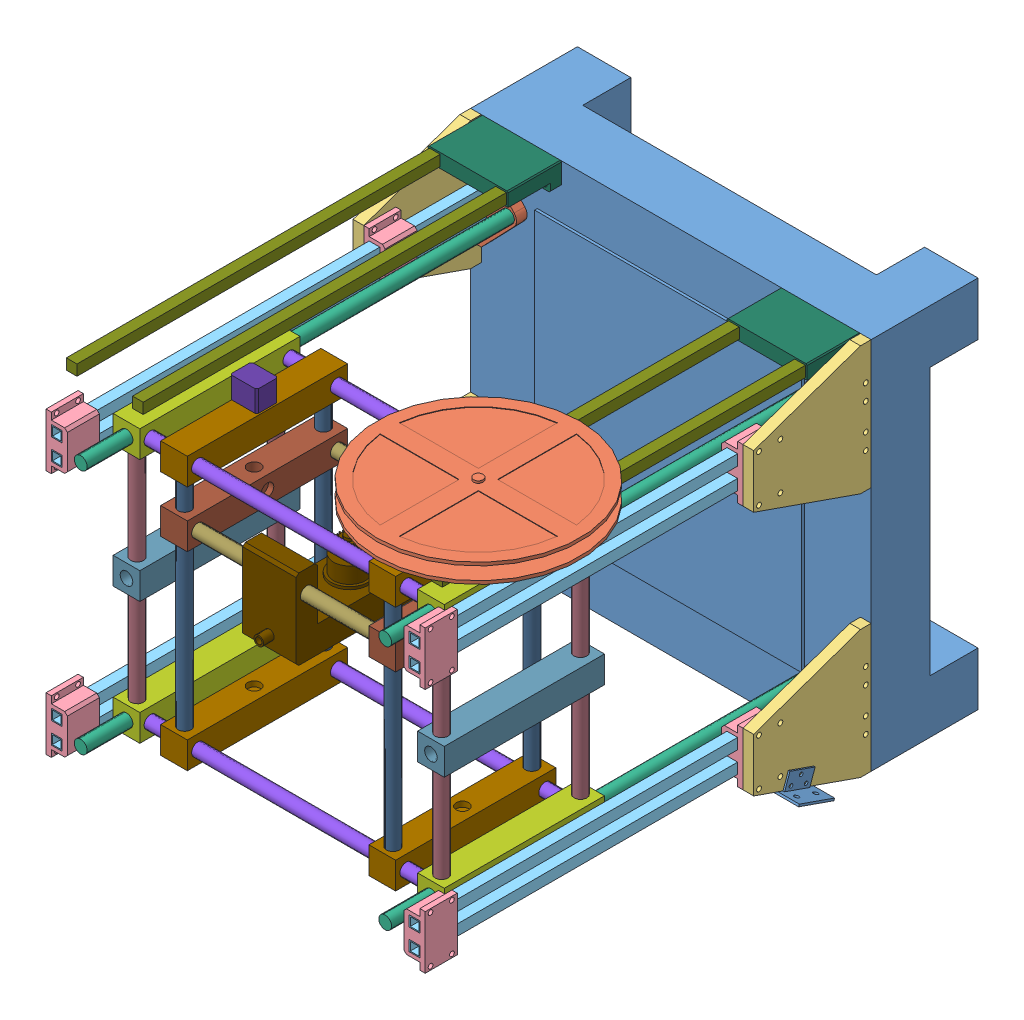
SolidWorks assembly ASSEMBLY, configuration Default. Lengths in mm.
Overall size (422.5 377.5 515.25).
70 component instances, 20 part files, 161 mates.
Components (placement in the parent):
- BASE-1: BASE [Default] at (119.7279 200.2172 245.0572) size (375 352.5 102.5)
- BOTTOM SUPPORT-1: BOTTOM SUPPORT [Default] at (292.2279 315.2172 355.0572) x (0 -1 0) z (0 0 -1) size (75 43 60)
- BOTTOM SUPPORT-2: BOTTOM SUPPORT [Default] at (-52.7721 315.2172 355.0572) x (0 1 0) z (0 0 -1) size (75 43 60)
- BOTTOM SUPPORT-3: BOTTOM SUPPORT [Default] at (-52.7721 85.2172 355.0572) x (0 1 0) z (0 0 -1) size (75 43 60)
- BOTTOM SUPPORT-4: BOTTOM SUPPORT [Default] at (292.2279 85.2172 355.0572) x (0 -1 0) z (0 0 -1) size (75 43 60)
- SIDE SUPPORT-1: SIDE SUPPORT [Default] at (297.2279 315.2172 350.0572) x (0 1 0) z (1 0 0) size (120 110 10)
- SIDE SUPPORT-2: SIDE SUPPORT [Default] at (297.2279 85.2172 350.0572) x (0 1 0) z (1 0 0) size (120 110 10)
- SIDE SUPPORT-3: SIDE SUPPORT [Default] at (-67.7721 85.2172 350.0572) x (0 1 0) z (1 0 0) size (120 110 10)
- SIDE SUPPORT-4: SIDE SUPPORT [Default] at (-67.7721 315.2172 350.0572) x (0 1 0) z (1 0 0) size (120 110 10)
- SIDE KNOB-1: SIDE KNOB [Default] at (287.2279 85.2172 425.0572) x (0 1 0) z (0 0 1) size (50 20 30)
- SIDE KNOB-2: SIDE KNOB [Default] at (287.2279 315.2172 455.0572) x (0 -1 0) z (0 0 -1) size (50 20 30)
- SIDE KNOB-3: SIDE KNOB [Default] at (-47.7721 315.2172 455.0572) x (0 1 0) z (0 0 -1) size (50 20 30)
- SIDE KNOB-4: SIDE KNOB [Default] at (-47.7721 85.2172 455.0572) x (0 1 0) z (0 0 -1) size (50 20 30)
- SQUARE ROD-1: SQUARE ROD [Default] at (-47.7721 75.2172 352.5572) size (10 10 400)
- SQUARE ROD-2: SQUARE ROD [Default] at (-47.7721 95.2172 352.5572) size (10 10 400)
- SQUARE ROD-3: SQUARE ROD [Default] at (-47.7721 305.2172 352.5572) size (10 10 400)
- SQUARE ROD-4: SQUARE ROD [Default] at (-47.7721 325.2172 352.5572) size (10 10 400)
- SQUARE ROD-5: SQUARE ROD [Default] at (287.2279 75.2172 352.5572) size (10 10 400)
- SQUARE ROD-6: SQUARE ROD [Default] at (287.2279 95.2172 352.5572) size (10 10 400)
- SQUARE ROD-7: SQUARE ROD [Default] at (287.2279 305.2172 352.5572) size (10 10 400)
- SQUARE ROD-8: SQUARE ROD [Default] at (287.2279 325.2172 352.5572) size (10 10 400)
- VERTICAL GUIDE-1: VERTICAL GUIDE [Default] at (-22.7721 85.2172 345.0572) x (0.761776 0.647841 0) z (0 0 1) size (12 12 410)
- VERTICAL GUIDE-2: VERTICAL GUIDE [Default] at (-22.7721 315.2172 345.0572) x (0.761776 0.647841 0) z (0 0 1) size (12 12 410)
- VERTICAL GUIDE-3: VERTICAL GUIDE [Default] at (262.2279 315.2172 345.0572) x (0.980683 -0.195602 0) z (0 0 1) size (12 12 410)
- VERTICAL GUIDE-4: VERTICAL GUIDE [Default] at (262.2279 85.2172 345.0572) x (0.443142 0.896451 0) z (0 0 1) size (12 12 410)
- new idea side knob-1: new idea side knob [Default] at (-22.7721 85.2172 637.218) x (0 -1 0) z (0 0 1) size (25 25 150)
- new idea side knob-2: new idea side knob [Default] at (-22.7721 315.2172 637.218) x (-1 0 0) z (0 0 1) size (25 25 150)
- new idea side knob-3: new idea side knob [Default] at (262.2279 315.2172 637.218) x (0 1 0) z (0 0 1) size (25 25 150)
- new idea side knob-4: new idea side knob [Default] at (262.2279 85.2172 637.218) size (25 25 150)
- FRONT GUIDE-1: FRONT GUIDE [Default] at (-15.2721 85.2172 702.218) x (0 -0.395369 -0.918522) z (1 0 0) size (12 12 270)
- FRONT GUIDE-2: FRONT GUIDE [Default] at (-15.2721 85.2172 572.218) x (0 -0.335752 -0.94195) z (1 0 0) size (12 12 270)
- FRONT GUIDE-3: FRONT GUIDE [Default] at (-15.2721 315.2172 702.218) x (0 0.992345 0.123494) z (1 0 0) size (12 12 270)
- FRONT GUIDE-4: FRONT GUIDE [Default] at (-15.2721 315.2172 572.218) x (0 0.188743 0.982026) z (1 0 0) size (12 12 270)
- front and back knob new idea-1: front and back knob new idea [Default] at (21.6908 85.2172 637.218) size (25 25 150)
- front and back knob new idea-2: front and back knob new idea [Default] at (216.6908 85.2172 637.218) size (25 25 150)
- front and back knob new idea-3: front and back knob new idea [Default] at (21.6908 315.2172 637.218) x (1 0 0) z (0 0 -1) size (25 25 150)
- front and back knob new idea-4: front and back knob new idea [Default] at (216.6908 315.2172 637.218) x (1 0 0) z (0 0 -1) size (25 25 150)
- HORIZONTAL ROD-1: HORIZONTAL ROD [Default] at (216.6908 92.7172 702.218) x (0.99237 0 -0.123294) z (0 1 0) size (12 12 215)
- HORIZONTAL ROD-2: HORIZONTAL ROD [Default] at (216.6908 92.7172 572.218) x (0.99237 0 -0.123294) z (0 1 0) size (12 12 215)
- HORIZONTAL ROD-3: HORIZONTAL ROD [Default] at (21.6908 92.7172 572.218) x (0.993205 0 0.116374) z (0 1 0) size (12 12 215)
- HORIZONTAL ROD-5: HORIZONTAL ROD [Default] at (21.6908 92.7172 702.218) x (0.993205 0 0.116374) z (0 1 0) size (12 12 215)
- new idea knob-1: new idea knob [Default] at (216.6908 262.7791 637.218) x (0 1 0) z (0 0 1) size (25 25 150)
- new idea knob-2: new idea knob [Default] at (21.6908 262.7791 637.218) x (0 -1 0) z (0 0 1) size (25 25 150)
- CENTER GUIDE-1: CENTER GUIDE [Default] at (209.1908 262.7791 702.218) x (0 0 1) z (-1 0 0) size (12 12 180)
- CENTER GUIDE-2: CENTER GUIDE [Default] at (209.1908 262.7791 572.218) x (0 0 1) z (-1 0 0) size (12 12 180)
- SIDE KNOB-5: SIDE KNOB [Default] at (-47.7721 85.2172 752.5572) x (0 1 0) z (0 0 -1) size (50 20 30)
- SIDE KNOB-6: SIDE KNOB [Default] at (-47.7721 315.2172 752.5572) x (0 1 0) z (0 0 -1) size (50 20 30)
- SIDE KNOB-7: SIDE KNOB [Default] at (287.2279 85.2172 752.5572) x (0 -1 0) z (0 0 -1) size (50 20 30)
- SIDE KNOB-8: SIDE KNOB [Default] at (287.2279 315.2172 752.5572) x (0 -1 0) z (0 0 -1) size (50 20 30)
- SIDE SIDE ROD-1: SIDE SIDE ROD [Default] at (-22.7721 207.7172 702.218) x (1 0 0) z (0 1 0) size (12 12 100)
- new idea center knob-2: new idea center knob [Default] at (-22.7721 200.2172 637.218) size (25 25 150)
- SIDE SIDE ROD-2: SIDE SIDE ROD [Default] at (-22.7721 192.7172 702.218) x (-0.837169 0 -0.546944) z (0 -1 0) size (12 12 100)
- SIDE SIDE ROD-3: SIDE SIDE ROD [Default] at (-22.7721 192.7172 572.218) x (-0.837169 0 -0.546944) z (0 -1 0) size (12 12 100)
- SIDE SIDE ROD-4: SIDE SIDE ROD [Default] at (-22.7721 307.7172 572.218) x (-0.837169 0 -0.546944) z (0 -1 0) size (12 12 100)
- SIDE SIDE ROD-5: SIDE SIDE ROD [Default] at (262.2279 192.7172 702.218) x (-0.837169 0 -0.546944) z (0 -1 0) size (12 12 100)
- new idea center knob-3: new idea center knob [Default] at (262.2279 200.2172 637.218) size (25 25 150)
- SIDE SIDE ROD-6: SIDE SIDE ROD [Default] at (262.2279 307.7172 702.218) x (-0.837169 0 -0.546944) z (0 -1 0) size (12 12 100)
- SIDE SIDE ROD-7: SIDE SIDE ROD [Default] at (262.2279 192.7172 572.218) x (-0.837169 0 -0.546944) z (0 -1 0) size (12 12 100)
- SIDE SIDE ROD-8: SIDE SIDE ROD [Default] at (262.2279 307.7172 572.218) x (-0.837169 0 -0.546944) z (0 -1 0) size (12 12 100)
- Part1-1: Part1 [Default] at (17.2279 375.2172 345.0572) x (0 -1 0) z (-1 0 0) size (21 50 75)
- Part1-2: Part1 [Default] at (297.2279 375.2172 345.0572) x (0 -1 0) z (-1 0 0) size (21 50 75)
- BACK RAIL-1: BACK RAIL [Default] at (290.7279 368.7172 385.0572) size (10 10 350)
- BACK RAIL-2: BACK RAIL [Default] at (228.7279 368.7172 385.0572) size (10 10 350)
- BACK RAIL-3: BACK RAIL [Default] at (-51.2721 368.7172 735.0572) x (0 -1 0) z (0 0 -1) size (10 10 350)
- BACK RAIL-5: BACK RAIL [Default] at (10.7279 368.7172 385.0572) size (10 10 350)
- MOTOR-2: MOTOR [Default] at (21.6908 349.2172 637.218) x (1 0 0) z (0 -1 0) size (25 20 21.5)
- MOTOR-3: MOTOR [Default] at (216.6908 349.2172 637.218) x (1 0 0) z (0 -1 0) size (25 20 21.5)
- new idea for nozzle-1: new idea for nozzle [Default] at (111.0525 245.2791 637.218) x (0 1 0) z (1 0 0) size (75 173.25 50)
- SCREEN SUPPORT-2: SCREEN SUPPORT [Default] at (302.2279 44.5865 416.452) x (-1 0 0) z (0 0.943858 -0.33035) size (50 35 17)
- TOP SUPPORT-1: TOP SUPPORT [Default] at (259.7279 364.7172 640.3028) size (190 46 190)
Mates (geometry in assembly coordinates):
- Coincident5: coincident anti-aligned: plane of BASE-1 through (297.2279 200.2172 295.0572) normal (-1 0 0); plane of BOTTOM SUPPORT-1 through (297.2279 352.7172 345.0572) normal (1 0 0)
- Coincident6: coincident anti-aligned: plane of BASE-1 through (119.7279 200.2172 295.0572) normal (0 0 1); plane of BOTTOM SUPPORT-1 through (292.2279 315.2172 295.0572) normal (0 0 -1)
- Coincident7: coincident anti-aligned: plane of BASE-1 through (119.7279 277.7172 295.0572) normal (0 1 0); plane of BOTTOM SUPPORT-1 through (297.2279 277.7172 345.0572) normal (0 -1 0)
- Coincident13: coincident anti-aligned: plane of BASE-1 through (-47.7721 200.2172 295.0572) normal (-1 0 0); plane of BOTTOM SUPPORT-2 through (-47.7721 277.7172 295.0572) normal (1 0 0)
- Coincident14: coincident anti-aligned: plane of BASE-1 through (119.7279 352.7172 295.0572) normal (0 -1 0); plane of BOTTOM SUPPORT-2 through (-57.7721 352.7172 345.0572) normal (0 1 0)
- Coincident15: coincident anti-aligned: plane of BASE-1 through (119.7279 200.2172 295.0572) normal (0 0 1); plane of BOTTOM SUPPORT-2 through (-52.7721 315.2172 295.0572) normal (0 0 -1)
- Coincident16: coincident anti-aligned: plane of BASE-1 through (-47.7721 200.2172 295.0572) normal (-1 0 0); plane of BOTTOM SUPPORT-3 through (-47.7721 47.7172 295.0572) normal (1 0 0)
- Coincident17: coincident anti-aligned: plane of BASE-1 through (119.7279 122.7172 295.0572) normal (0 -1 0); plane of BOTTOM SUPPORT-3 through (-57.7721 122.7172 345.0572) normal (0 1 0)
- Coincident18: coincident anti-aligned: plane of BASE-1 through (119.7279 200.2172 295.0572) normal (0 0 1); plane of BOTTOM SUPPORT-3 through (-52.7721 85.2172 295.0572) normal (0 0 -1)
- Coincident19: coincident anti-aligned: plane of BASE-1 through (287.2279 200.2172 295.0572) normal (1 0 0); plane of BOTTOM SUPPORT-4 through (287.2279 122.7172 295.0572) normal (-1 0 0)
- Coincident20: coincident anti-aligned: plane of BASE-1 through (119.7279 122.7172 295.0572) normal (0 -1 0); plane of BOTTOM SUPPORT-4 through (297.2279 122.7172 345.0572) normal (0 1 0)
- Coincident21: coincident anti-aligned: plane of BASE-1 through (119.7279 200.2172 295.0572) normal (0 0 1); plane of BOTTOM SUPPORT-4 through (292.2279 85.2172 295.0572) normal (0 0 -1)
- Concentric1: concentric anti-aligned: cylinder of BOTTOM SUPPORT-1 through (288.2279 287.7172 350.0572) axis (1 0 0) radius 2.25; cylinder of SIDE SUPPORT-1 through (307.2279 287.7172 350.0572) axis (-1 0 0) radius 2.25
- Concentric2: concentric anti-aligned: cylinder of BOTTOM SUPPORT-1 through (288.2279 342.7172 350.0572) axis (1 0 0) radius 2.25; cylinder of SIDE SUPPORT-1 through (307.2279 342.7172 350.0572) axis (-1 0 0) radius 2.25
- Concentric3: concentric anti-aligned: cylinder of BOTTOM SUPPORT-1 through (288.2279 327.7172 350.0572) axis (1 0 0) radius 2.25; cylinder of SIDE SUPPORT-1 through (307.2279 327.7172 350.0572) axis (-1 0 0) radius 2.25
- Coincident22: coincident aligned: plane of BASE-1 through (307.2279 25.2172 345.0572) normal (1 0 0); plane of SIDE SUPPORT-1 through (307.2279 315.2172 350.0572) normal (1 0 0)
- Concentric4: concentric anti-aligned: cylinder of BOTTOM SUPPORT-4 through (288.2279 57.7172 350.0572) axis (1 0 0) radius 2.25; cylinder of SIDE SUPPORT-2 through (307.2279 57.7172 350.0572) axis (-1 0 0) radius 2.25
- Concentric5: concentric anti-aligned: cylinder of BOTTOM SUPPORT-4 through (288.2279 112.7172 350.0572) axis (1 0 0) radius 2.25; cylinder of SIDE SUPPORT-2 through (307.2279 112.7172 350.0572) axis (-1 0 0) radius 2.25
- Coincident24: coincident aligned: plane of BASE-1 through (307.2279 25.2172 345.0572) normal (1 0 0); plane of SIDE SUPPORT-2 through (307.2279 85.2172 350.0572) normal (1 0 0)
- Concentric6: concentric aligned: cylinder of BOTTOM SUPPORT-3 through (-48.7721 57.7172 350.0572) axis (-1 0 0) radius 2.25; cylinder of SIDE SUPPORT-3 through (-57.7721 57.7172 350.0572) axis (-1 0 0) radius 2.25
- Concentric7: concentric aligned: cylinder of BOTTOM SUPPORT-3 through (-48.7721 112.7172 350.0572) axis (-1 0 0) radius 2.25; cylinder of SIDE SUPPORT-3 through (-57.7721 112.7172 350.0572) axis (-1 0 0) radius 2.25
- Coincident25: coincident aligned: plane of BASE-1 through (-67.7721 25.2172 345.0572) normal (-1 0 0); plane of SIDE SUPPORT-3 through (-67.7721 85.2172 350.0572) normal (-1 0 0)
- Concentric8: concentric aligned: cylinder of BOTTOM SUPPORT-2 through (-48.7721 287.7172 350.0572) axis (-1 0 0) radius 2.25; cylinder of SIDE SUPPORT-4 through (-57.7721 287.7172 350.0572) axis (-1 0 0) radius 2.25
- Concentric9: concentric aligned: cylinder of BOTTOM SUPPORT-2 through (-48.7721 342.7172 350.0572) axis (-1 0 0) radius 2.25; cylinder of SIDE SUPPORT-4 through (-57.7721 342.7172 350.0572) axis (-1 0 0) radius 2.25
- Coincident26: coincident aligned: plane of BASE-1 through (-67.7721 25.2172 345.0572) normal (-1 0 0); plane of SIDE SUPPORT-4 through (-67.7721 315.2172 350.0572) normal (-1 0 0)
- Coincident28: coincident anti-aligned: line of SIDE SUPPORT-2 through (307.2279 60.2172 455.0572) axis (-1 0 0); line of SIDE KNOB-1 through (292.2279 60.2172 455.0572) axis (1 0 0)
- Coincident29: coincident aligned: line of SIDE SUPPORT-2 through (307.2279 110.2172 455.0572) axis (-1 0 0); line of SIDE KNOB-1 through (297.2279 110.2172 455.0572) axis (-1 0 0)
- Coincident30: coincident aligned: plane of SIDE SUPPORT-2 through (307.2279 60.2172 455.0572) normal (0 0 1); plane of SIDE KNOB-1 through (287.2279 85.2172 455.0572) normal (0 0 1)
- Coincident31: coincident anti-aligned: line of SIDE SUPPORT-2 through (297.2279 110.2172 455.0572) axis (0 -1 0); line of SIDE KNOB-1 through (297.2279 60.2172 455.0572) axis (0 1 0)
- Coincident33: coincident aligned: line of SIDE SUPPORT-1 through (307.2279 290.2172 455.0572) axis (-1 0 0); line of SIDE KNOB-2 through (297.2279 290.2172 455.0572) axis (-1 0 0)
- Coincident34: coincident anti-aligned: line of SIDE SUPPORT-1 through (307.2279 340.2172 455.0572) axis (-1 0 0); line of SIDE KNOB-2 through (292.2279 340.2172 455.0572) axis (1 0 0)
- Coincident35: coincident aligned: plane of SIDE SUPPORT-1 through (307.2279 290.2172 455.0572) normal (0 0 1); plane of SIDE KNOB-2 through (287.2279 315.2172 455.0572) normal (0 0 1)
- Coincident36: coincident aligned: line of SIDE SUPPORT-1 through (297.2279 340.2172 455.0572) axis (0 -1 0); line of SIDE KNOB-2 through (297.2279 340.2172 455.0572) axis (0 -1 0)
- Coincident37: coincident aligned: line of SIDE SUPPORT-4 through (-57.7721 290.2172 455.0572) axis (-1 0 0); line of SIDE KNOB-3 through (-52.7721 290.2172 455.0572) axis (-1 0 0)
- Coincident38: coincident anti-aligned: line of SIDE SUPPORT-4 through (-57.7721 340.2172 455.0572) axis (-1 0 0); line of SIDE KNOB-3 through (-57.7721 340.2172 455.0572) axis (1 0 0)
- Coincident41: coincident anti-aligned: line of SIDE SUPPORT-4 through (-57.7721 340.2172 455.0572) axis (0 -1 0); line of SIDE KNOB-3 through (-57.7721 290.2172 455.0572) axis (0 1 0)
- Coincident42: coincident aligned: line of SIDE SUPPORT-3 through (-57.7721 60.2172 455.0572) axis (-1 0 0); line of SIDE KNOB-4 through (-52.7721 60.2172 455.0572) axis (-1 0 0)
- Coincident43: coincident anti-aligned: line of SIDE SUPPORT-3 through (-57.7721 110.2172 455.0572) axis (-1 0 0); line of SIDE KNOB-4 through (-57.7721 110.2172 455.0572) axis (1 0 0)
- Coincident44: coincident aligned: plane of SIDE SUPPORT-3 through (-57.7721 60.2172 455.0572) normal (0 0 1); plane of SIDE KNOB-4 through (-47.7721 85.2172 455.0572) normal (0 0 1)
- Coincident45: coincident anti-aligned: line of SIDE SUPPORT-3 through (-57.7721 110.2172 455.0572) axis (0 -1 0); line of SIDE KNOB-4 through (-57.7721 60.2172 455.0572) axis (0 1 0)
- Coincident48: coincident anti-aligned: plane of BOTTOM SUPPORT-3 through (-52.7721 85.2172 352.5572) normal (1 0 0); plane of SQUARE ROD-1 through (-52.7721 70.2172 752.5572) normal (-1 0 0)
- Coincident49: coincident anti-aligned: plane of BOTTOM SUPPORT-3 through (-52.7721 85.2172 352.5572) normal (0 0 1); plane of SQUARE ROD-1 through (-47.7721 75.2172 352.5572) normal (0 0 -1)
- Coincident50: coincident anti-aligned: plane of BOTTOM SUPPORT-3 through (-52.7721 70.2172 352.5572) normal (0 1 0); plane of SQUARE ROD-1 through (-52.7721 70.2172 752.5572) normal (0 -1 0)
- Coincident52: coincident anti-aligned: plane of BOTTOM SUPPORT-3 through (-52.7721 85.2172 352.5572) normal (1 0 0); plane of SQUARE ROD-2 through (-52.7721 90.2172 752.5572) normal (-1 0 0)
- Coincident53: coincident anti-aligned: plane of BOTTOM SUPPORT-3 through (-52.7721 90.2172 352.5572) normal (0 1 0); plane of SQUARE ROD-2 through (-52.7721 90.2172 752.5572) normal (0 -1 0)
- Coincident54: coincident anti-aligned: plane of BOTTOM SUPPORT-3 through (-52.7721 85.2172 352.5572) normal (0 0 1); plane of SQUARE ROD-2 through (-47.7721 95.2172 352.5572) normal (0 0 -1)
- Coincident55: coincident anti-aligned: plane of BOTTOM SUPPORT-2 through (-42.7721 315.2172 352.5572) normal (-1 0 0); plane of SQUARE ROD-3 through (-42.7721 300.2172 752.5572) normal (1 0 0)
- Coincident56: coincident anti-aligned: plane of BOTTOM SUPPORT-2 through (-52.7721 310.2172 352.5572) normal (0 -1 0); plane of SQUARE ROD-3 through (-52.7721 310.2172 752.5572) normal (0 1 0)
- Coincident57: coincident anti-aligned: plane of BOTTOM SUPPORT-2 through (-52.7721 315.2172 352.5572) normal (0 0 1); plane of SQUARE ROD-3 through (-47.7721 305.2172 352.5572) normal (0 0 -1)
- Coincident58: coincident anti-aligned: plane of BOTTOM SUPPORT-2 through (-42.7721 315.2172 352.5572) normal (-1 0 0); plane of SQUARE ROD-4 through (-42.7721 320.2172 752.5572) normal (1 0 0)
- Coincident59: coincident anti-aligned: plane of BOTTOM SUPPORT-2 through (-52.7721 320.2172 352.5572) normal (0 1 0); plane of SQUARE ROD-4 through (-52.7721 320.2172 752.5572) normal (0 -1 0)
- Coincident60: coincident anti-aligned: plane of BOTTOM SUPPORT-2 through (-52.7721 315.2172 352.5572) normal (0 0 1); plane of SQUARE ROD-4 through (-47.7721 325.2172 352.5572) normal (0 0 -1)
- Coincident61: coincident anti-aligned: plane of BOTTOM SUPPORT-4 through (292.2279 70.2172 352.5572) normal (0 1 0); plane of SQUARE ROD-5 through (282.2279 70.2172 752.5572) normal (0 -1 0)
- Coincident62: coincident anti-aligned: plane of BOTTOM SUPPORT-4 through (292.2279 85.2172 352.5572) normal (-1 0 0); plane of SQUARE ROD-5 through (292.2279 70.2172 752.5572) normal (1 0 0)
- Coincident63: coincident anti-aligned: plane of BOTTOM SUPPORT-4 through (292.2279 85.2172 352.5572) normal (0 0 1); plane of SQUARE ROD-5 through (287.2279 75.2172 352.5572) normal (0 0 -1)
- Coincident64: coincident anti-aligned: plane of BOTTOM SUPPORT-4 through (282.2279 85.2172 352.5572) normal (1 0 0); plane of SQUARE ROD-6 through (282.2279 90.2172 752.5572) normal (-1 0 0)
- Coincident65: coincident anti-aligned: plane of BOTTOM SUPPORT-4 through (292.2279 90.2172 352.5572) normal (0 1 0); plane of SQUARE ROD-6 through (282.2279 90.2172 752.5572) normal (0 -1 0)
- Coincident66: coincident anti-aligned: plane of BOTTOM SUPPORT-4 through (292.2279 85.2172 352.5572) normal (0 0 1); plane of SQUARE ROD-6 through (287.2279 95.2172 352.5572) normal (0 0 -1)
- Coincident67: coincident anti-aligned: plane of BOTTOM SUPPORT-1 through (292.2279 315.2172 352.5572) normal (-1 0 0); plane of SQUARE ROD-7 through (292.2279 300.2172 752.5572) normal (1 0 0)
- Coincident68: coincident anti-aligned: plane of BOTTOM SUPPORT-1 through (292.2279 310.2172 352.5572) normal (0 -1 0); plane of SQUARE ROD-7 through (282.2279 310.2172 752.5572) normal (0 1 0)
- Coincident69: coincident anti-aligned: plane of BOTTOM SUPPORT-1 through (292.2279 315.2172 352.5572) normal (0 0 1); plane of SQUARE ROD-7 through (287.2279 305.2172 352.5572) normal (0 0 -1)
- Coincident70: coincident anti-aligned: plane of BOTTOM SUPPORT-1 through (292.2279 315.2172 352.5572) normal (0 0 1); plane of SQUARE ROD-8 through (287.2279 325.2172 352.5572) normal (0 0 -1)
- Coincident71: coincident anti-aligned: plane of BOTTOM SUPPORT-1 through (292.2279 330.2172 352.5572) normal (0 -1 0); plane of SQUARE ROD-8 through (282.2279 330.2172 752.5572) normal (0 1 0)
- Coincident72: coincident anti-aligned: plane of BOTTOM SUPPORT-1 through (282.2279 315.2172 352.5572) normal (1 0 0); plane of SQUARE ROD-8 through (282.2279 320.2172 752.5572) normal (-1 0 0)
- Concentric12: concentric anti-aligned: cylinder of BOTTOM SUPPORT-3 through (-22.7721 85.2172 345.0572) axis (0 0 1) radius 6; cylinder of VERTICAL GUIDE-1 through (-22.7721 85.2172 755.0572) axis (0 0 -1) radius 6
- Coincident73: coincident anti-aligned: circle of BOTTOM SUPPORT-3; circle of VERTICAL GUIDE-1
- Coincident74: coincident anti-aligned: circle of BOTTOM SUPPORT-2; circle of VERTICAL GUIDE-2
- Concentric13: concentric anti-aligned: cylinder of BOTTOM SUPPORT-1 through (262.2279 315.2172 345.0572) axis (0 0 1) radius 6; cylinder of VERTICAL GUIDE-3 through (262.2279 315.2172 755.0572) axis (0 0 -1) radius 6
- Coincident75: coincident anti-aligned: circle of BOTTOM SUPPORT-1; circle of VERTICAL GUIDE-3
- Concentric14: concentric anti-aligned: cylinder of BOTTOM SUPPORT-4 through (262.2279 85.2172 345.0572) axis (0 0 1) radius 6; cylinder of VERTICAL GUIDE-4 through (262.2279 85.2172 755.0572) axis (0 0 -1) radius 6
- Coincident76: coincident anti-aligned: circle of BOTTOM SUPPORT-4; circle of VERTICAL GUIDE-4
- Concentric15: concentric aligned: cylinder of VERTICAL GUIDE-1 through (-22.7721 85.2172 755.0572) axis (0 0 -1) radius 6; cylinder of new idea side knob-1 through (-22.7721 85.2172 712.218) axis (0 0 -1) radius 6
- Concentric16: concentric aligned: cylinder of VERTICAL GUIDE-2 through (-22.7721 315.2172 755.0572) axis (0 0 -1) radius 6; cylinder of new idea side knob-2 through (-22.7721 315.2172 712.218) axis (0 0 -1) radius 6
- Concentric17: concentric aligned: cylinder of VERTICAL GUIDE-3 through (262.2279 315.2172 755.0572) axis (0 0 -1) radius 6; cylinder of new idea side knob-3 through (262.2279 315.2172 712.218) axis (0 0 -1) radius 6
- Concentric18: concentric aligned: cylinder of VERTICAL GUIDE-4 through (262.2279 85.2172 755.0572) axis (0 0 -1) radius 6; cylinder of new idea side knob-4 through (262.2279 85.2172 712.218) axis (0 0 -1) radius 6
- Concentric19: concentric anti-aligned: cylinder of new idea side knob-1 through (-15.2721 85.2172 702.218) axis (1 0 0) radius 6; cylinder of FRONT GUIDE-1 through (254.7279 85.2172 702.218) axis (-1 0 0) radius 6
- Coincident77: coincident aligned: circle of new idea side knob-1; circle of FRONT GUIDE-1
- Parallel2: parallel anti-aligned: plane of new idea side knob-1 through (-10.2721 97.7172 712.218) normal (1 0 0); plane of new idea side knob-4 through (249.7279 72.7172 712.218) normal (-1 0 0)
- Concentric20: concentric aligned: cylinder of new idea side knob-4 through (254.7279 85.2172 702.218) axis (-1 0 0) radius 6; cylinder of FRONT GUIDE-1 through (254.7279 85.2172 702.218) axis (-1 0 0) radius 6
- Coincident81: coincident aligned: circle of new idea side knob-1; circle of FRONT GUIDE-2
- Coincident82: coincident aligned: circle of new idea side knob-4; cylinder of FRONT GUIDE-2 through (254.7279 85.2172 572.218) axis (-1 0 0) radius 6
- Concentric21: concentric aligned: cylinder of new idea side knob-3 through (254.7279 315.2172 702.218) axis (-1 0 0) radius 6; cylinder of FRONT GUIDE-3 through (254.7279 315.2172 702.218) axis (-1 0 0) radius 6
- Coincident83: coincident anti-aligned: circle of new idea side knob-3; circle of FRONT GUIDE-3
- Concentric22: concentric anti-aligned: cylinder of new idea side knob-2 through (-15.2721 315.2172 702.218) axis (1 0 0) radius 6; cylinder of FRONT GUIDE-3 through (254.7279 315.2172 702.218) axis (-1 0 0) radius 6
- Concentric23: concentric anti-aligned: cylinder of new idea side knob-2 through (-15.2721 315.2172 572.218) axis (1 0 0) radius 6; cylinder of FRONT GUIDE-4 through (254.7279 315.2172 572.218) axis (-1 0 0) radius 6
- Coincident84: coincident aligned: circle of new idea side knob-2; circle of FRONT GUIDE-4
- Coincident85: coincident aligned: plane of new idea side knob-1 through (-22.7721 85.2172 712.218) normal (0 0 1); plane of new idea side knob-2 through (-22.7721 315.2172 712.218) normal (0 0 1)
- Concentric24: concentric aligned: cylinder of FRONT GUIDE-1 through (254.7279 85.2172 702.218) axis (-1 0 0) radius 6; cylinder of front and back knob new idea-1 through (34.1908 85.2172 702.218) axis (-1 0 0) radius 6
- Concentric25: concentric aligned: cylinder of FRONT GUIDE-2 through (254.7279 85.2172 572.218) axis (-1 0 0) radius 6; cylinder of front and back knob new idea-1 through (34.1908 85.2172 572.218) axis (-1 0 0) radius 6
- Concentric27: concentric aligned: cylinder of FRONT GUIDE-1 through (254.7279 85.2172 702.218) axis (-1 0 0) radius 6; cylinder of front and back knob new idea-2 through (229.1908 85.2172 702.218) axis (-1 0 0) radius 6
- Concentric28: concentric aligned: cylinder of FRONT GUIDE-2 through (254.7279 85.2172 572.218) axis (-1 0 0) radius 6; cylinder of front and back knob new idea-2 through (229.1908 85.2172 572.218) axis (-1 0 0) radius 6
- Concentric29: concentric aligned: cylinder of FRONT GUIDE-3 through (254.7279 315.2172 702.218) axis (-1 0 0) radius 6; cylinder of front and back knob new idea-3 through (34.1908 315.2172 702.218) axis (-1 0 0) radius 6
- Concentric30: concentric aligned: cylinder of FRONT GUIDE-4 through (254.7279 315.2172 572.218) axis (-1 0 0) radius 6; cylinder of front and back knob new idea-3 through (34.1908 315.2172 572.218) axis (-1 0 0) radius 6
- Concentric31: concentric aligned: cylinder of FRONT GUIDE-3 through (254.7279 315.2172 702.218) axis (-1 0 0) radius 6; cylinder of front and back knob new idea-4 through (229.1908 315.2172 702.218) axis (-1 0 0) radius 6
- Concentric32: concentric aligned: cylinder of FRONT GUIDE-4 through (254.7279 315.2172 572.218) axis (-1 0 0) radius 6; cylinder of front and back knob new idea-4 through (229.1908 315.2172 572.218) axis (-1 0 0) radius 6
- Concentric35: concentric anti-aligned: cylinder of front and back knob new idea-2 through (216.6908 92.7172 702.218) axis (0 1 0) radius 6; cylinder of HORIZONTAL ROD-1 through (216.6908 307.7172 702.218) axis (0 -1 0) radius 6
- Coincident94: coincident aligned: circle of front and back knob new idea-2; circle of HORIZONTAL ROD-1
- Coincident95: coincident anti-aligned: circle of front and back knob new idea-4; circle of HORIZONTAL ROD-1
- Concentric36: concentric aligned: cylinder of front and back knob new idea-4 through (216.6908 307.7172 572.218) axis (0 -1 0) radius 6; cylinder of HORIZONTAL ROD-2 through (216.6908 307.7172 572.218) axis (0 -1 0) radius 6
- Coincident96: coincident anti-aligned: circle of front and back knob new idea-4; circle of HORIZONTAL ROD-2
- Concentric39: concentric anti-aligned: cylinder of front and back knob new idea-1 through (21.6908 92.7172 572.218) axis (0 1 0) radius 6; cylinder of HORIZONTAL ROD-3 through (21.6908 307.7172 572.218) axis (0 -1 0) radius 6
- Coincident99: coincident aligned: circle of front and back knob new idea-1; circle of HORIZONTAL ROD-3
- Concentric40: concentric anti-aligned: cylinder of front and back knob new idea-1 through (21.6908 92.7172 702.218) axis (0 1 0) radius 6; cylinder of HORIZONTAL ROD-5 through (21.6908 307.7172 702.218) axis (0 -1 0) radius 6
- Coincident100: coincident aligned: circle of front and back knob new idea-1; circle of HORIZONTAL ROD-5
- Coincident102: coincident anti-aligned: circle of front and back knob new idea-3; circle of HORIZONTAL ROD-5
- Concentric45: concentric anti-aligned: cylinder of HORIZONTAL ROD-1 through (216.6908 307.7172 702.218) axis (0 -1 0) radius 6; cylinder of new idea knob-1 through (216.6908 250.2791 702.218) axis (0 1 0) radius 6
- Concentric46: concentric aligned: cylinder of HORIZONTAL ROD-5 through (21.6908 307.7172 702.218) axis (0 -1 0) radius 6; cylinder of new idea knob-2 through (21.6908 275.2791 702.218) axis (0 -1 0) radius 6
- Concentric47: concentric aligned: cylinder of HORIZONTAL ROD-3 through (21.6908 307.7172 572.218) axis (0 -1 0) radius 6; cylinder of new idea knob-2 through (21.6908 275.2791 572.218) axis (0 -1 0) radius 6
- Coincident108: coincident anti-aligned: circle of new idea knob-2; circle of CENTER GUIDE-1
- Coincident109: coincident aligned: circle of new idea knob-1; circle of CENTER GUIDE-1
- Coincident110: coincident aligned: circle of new idea knob-1; circle of CENTER GUIDE-2
- Coincident111: coincident anti-aligned: plane of SQUARE ROD-1 through (-52.7721 70.2172 752.5572) normal (-1 0 0); plane of SIDE KNOB-5 through (-52.7721 70.2172 722.5572) normal (1 0 0)
- Coincident112: coincident anti-aligned: plane of SQUARE ROD-1 through (-52.7721 80.2172 752.5572) normal (0 1 0); plane of SIDE KNOB-5 through (-42.7721 80.2172 722.5572) normal (0 -1 0)
- Coincident113: coincident aligned: plane of SQUARE ROD-1 through (-47.7721 75.2172 752.5572) normal (0 0 1); plane of SIDE KNOB-5 through (-47.7721 85.2172 752.5572) normal (0 0 1)
- Coincident114: coincident anti-aligned: plane of SQUARE ROD-3 through (-52.7721 300.2172 752.5572) normal (-1 0 0); plane of SIDE KNOB-6 through (-52.7721 300.2172 722.5572) normal (1 0 0)
- Coincident115: coincident anti-aligned: plane of SQUARE ROD-3 through (-52.7721 300.2172 752.5572) normal (0 -1 0); plane of SIDE KNOB-6 through (-52.7721 300.2172 722.5572) normal (0 1 0)
- Coincident116: coincident aligned: plane of SQUARE ROD-3 through (-47.7721 305.2172 752.5572) normal (0 0 1); plane of SIDE KNOB-6 through (-47.7721 315.2172 752.5572) normal (0 0 1)
- Coincident119: coincident anti-aligned: plane of SQUARE ROD-5 through (282.2279 70.2172 752.5572) normal (-1 0 0); plane of SIDE KNOB-7 through (282.2279 80.2172 722.5572) normal (1 0 0)
- Coincident120: coincident aligned: plane of SQUARE ROD-5 through (287.2279 75.2172 752.5572) normal (0 0 1); plane of SIDE KNOB-7 through (287.2279 85.2172 752.5572) normal (0 0 1)
- Coincident121: coincident anti-aligned: plane of SQUARE ROD-5 through (282.2279 70.2172 752.5572) normal (0 -1 0); plane of SIDE KNOB-7 through (292.2279 70.2172 722.5572) normal (0 1 0)
- Coincident122: coincident anti-aligned: plane of SQUARE ROD-8 through (292.2279 320.2172 752.5572) normal (1 0 0); plane of SIDE KNOB-8 through (292.2279 330.2172 722.5572) normal (-1 0 0)
- Coincident123: coincident anti-aligned: plane of SQUARE ROD-8 through (282.2279 330.2172 752.5572) normal (0 1 0); plane of SIDE KNOB-8 through (292.2279 330.2172 722.5572) normal (0 -1 0)
- Coincident124: coincident aligned: plane of SQUARE ROD-8 through (287.2279 325.2172 752.5572) normal (0 0 1); plane of SIDE KNOB-8 through (287.2279 315.2172 752.5572) normal (0 0 1)
- Coincident125: coincident anti-aligned: circle of new idea side knob-2; circle of SIDE SIDE ROD-1
- Coincident126: coincident aligned: circle of SIDE SIDE ROD-1; circle of new idea center knob-2
- Coincident127: coincident aligned: circle of new idea center knob-2; circle of SIDE SIDE ROD-2
- Coincident128: coincident anti-aligned: circle of new idea side knob-1; circle of SIDE SIDE ROD-3
- Coincident129: coincident anti-aligned: circle of new idea center knob-2; circle of SIDE SIDE ROD-4
- Coincident131: coincident anti-aligned: circle of new idea side knob-4; circle of SIDE SIDE ROD-5
- Coincident132: coincident aligned: circle of SIDE SIDE ROD-5; circle of new idea center knob-3
- Coincident134: coincident aligned: circle of new idea side knob-3; circle of SIDE SIDE ROD-6
- Coincident135: coincident aligned: circle of new idea center knob-3; circle of SIDE SIDE ROD-7
- Coincident136: coincident aligned: circle of new idea side knob-3; circle of SIDE SIDE ROD-8
- Coincident137: coincident anti-aligned: plane of SIDE SUPPORT-4 through (-57.7721 315.2172 350.0572) normal (1 0 0); plane of Part1-1 through (-57.7721 375.2172 345.0572) normal (-1 0 0)
- Coincident138: coincident aligned: plane of BASE-1 through (-67.7721 375.2172 345.0572) normal (0 1 0); plane of Part1-1 through (-57.7721 375.2172 345.0572) normal (0 1 0)
- Coincident139: coincident anti-aligned: plane of BASE-1 through (119.7279 200.2172 345.0572) normal (0 0 1); plane of Part1-1 through (-57.7721 375.2172 345.0572) normal (0 0 -1)
- Coincident140: coincident anti-aligned: plane of SIDE SUPPORT-1 through (297.2279 315.2172 350.0572) normal (-1 0 0); plane of Part1-2 through (297.2279 375.2172 345.0572) normal (1 0 0)
- Coincident141: coincident aligned: plane of BASE-1 through (-67.7721 375.2172 345.0572) normal (0 1 0); plane of Part1-2 through (222.2279 375.2172 345.0572) normal (0 1 0)
- Coincident142: coincident anti-aligned: plane of BASE-1 through (119.7279 200.2172 345.0572) normal (0 0 1); plane of Part1-2 through (222.2279 375.2172 345.0572) normal (0 0 -1)
- Coincident145: coincident anti-aligned: plane of Part1-2 through (295.7279 375.2172 385.0572) normal (-1 0 0); plane of BACK RAIL-1 through (295.7279 363.7172 735.0572) normal (1 0 0)
- Coincident148: coincident anti-aligned: plane of Part1-2 through (297.2279 375.2172 385.0572) normal (0 0 1); plane of BACK RAIL-1 through (290.7279 368.7172 385.0572) normal (0 0 -1)
- Coincident149: coincident anti-aligned: plane of Part1-2 through (297.2279 363.7172 385.0572) normal (0 1 0); plane of BACK RAIL-1 through (285.7279 363.7172 735.0572) normal (0 -1 0)
- Coincident150: coincident anti-aligned: plane of Part1-2 through (233.7279 375.2172 385.0572) normal (-1 0 0); plane of BACK RAIL-2 through (233.7279 363.7172 735.0572) normal (1 0 0)
- Coincident151: coincident anti-aligned: plane of Part1-2 through (297.2279 373.7172 385.0572) normal (0 -1 0); plane of BACK RAIL-2 through (223.7279 373.7172 735.0572) normal (0 1 0)
- Coincident152: coincident anti-aligned: plane of Part1-2 through (297.2279 375.2172 385.0572) normal (0 0 1); plane of BACK RAIL-2 through (228.7279 368.7172 385.0572) normal (0 0 -1)
- Coincident155: coincident anti-aligned: plane of Part1-1 through (17.2279 363.7172 385.0572) normal (0 1 0); plane of BACK RAIL-5 through (5.7279 363.7172 735.0572) normal (0 -1 0)
- Coincident156: coincident anti-aligned: plane of Part1-1 through (5.7279 375.2172 385.0572) normal (1 0 0); plane of BACK RAIL-5 through (5.7279 363.7172 735.0572) normal (-1 0 0)
- Coincident157: coincident anti-aligned: plane of Part1-1 through (17.2279 375.2172 385.0572) normal (0 0 1); plane of BACK RAIL-5 through (10.7279 368.7172 385.0572) normal (0 0 -1)
- Coincident158: coincident anti-aligned: plane of Part1-1 through (17.2279 363.7172 385.0572) normal (0 1 0); plane of BACK RAIL-3 through (-46.2721 363.7172 385.0572) normal (0 -1 0)
- Coincident159: coincident anti-aligned: plane of Part1-1 through (-56.2721 375.2172 385.0572) normal (1 0 0); plane of BACK RAIL-3 through (-56.2721 373.7172 385.0572) normal (-1 0 0)
- Coincident160: coincident anti-aligned: plane of Part1-1 through (17.2279 375.2172 385.0572) normal (0 0 1); plane of BACK RAIL-3 through (-51.2721 368.7172 385.0572) normal (0 0 -1)
- Coincident162: coincident anti-aligned: plane of front and back knob new idea-3 through (9.1908 327.7172 562.218) normal (0 1 0); plane of MOTOR-2 through (21.6908 327.7172 637.218) normal (0 -1 0)
- Concentric48: concentric aligned: circle of front and back knob new idea-3; circle of MOTOR-2
- Coincident164: coincident anti-aligned: plane of front and back knob new idea-4 through (204.1908 327.7172 562.218) normal (0 1 0); plane of MOTOR-3 through (216.6908 327.7172 637.218) normal (0 -1 0)
- Concentric50: concentric aligned: circle of front and back knob new idea-4; circle of MOTOR-3
- Concentric51: concentric aligned: cylinder of CENTER GUIDE-1 through (29.1908 262.7791 702.218) axis (1 0 0) radius 6; cylinder of new idea for nozzle-1 through (86.0525 262.7791 702.218) axis (1 0 0) radius 6
- Concentric52: concentric aligned: cylinder of CENTER GUIDE-2 through (29.1908 262.7791 572.218) axis (1 0 0) radius 6; cylinder of new idea for nozzle-1 through (86.0525 262.7791 572.218) axis (1 0 0) radius 6
- Coincident169: coincident anti-aligned: plane of SIDE SUPPORT-2 through (307.2279 25.2172 355.0572) normal (0 -0.943858 0.33035); plane of SCREEN SUPPORT-2 through (302.2279 46.4742 415.7913) normal (0 0.943858 -0.33035)
- Coincident170: coincident anti-aligned: plane of SIDE SUPPORT-2 through (297.2279 85.2172 350.0572) normal (-1 0 0); plane of SCREEN SUPPORT-2 through (297.2279 60.6321 410.8361) normal (1 0 0)
- Coincident171: coincident anti-aligned: plane of BACK RAIL-1 through (295.7279 363.7172 735.0572) normal (1 0 0); plane of TOP SUPPORT-1 through (295.7279 363.7172 690.3028) normal (-1 0 0)
- Coincident172: coincident anti-aligned: plane of BACK RAIL-1 through (285.7279 373.7172 735.0572) normal (0 1 0); plane of TOP SUPPORT-1 through (285.7279 373.7172 690.3028) normal (0 -1 0)
